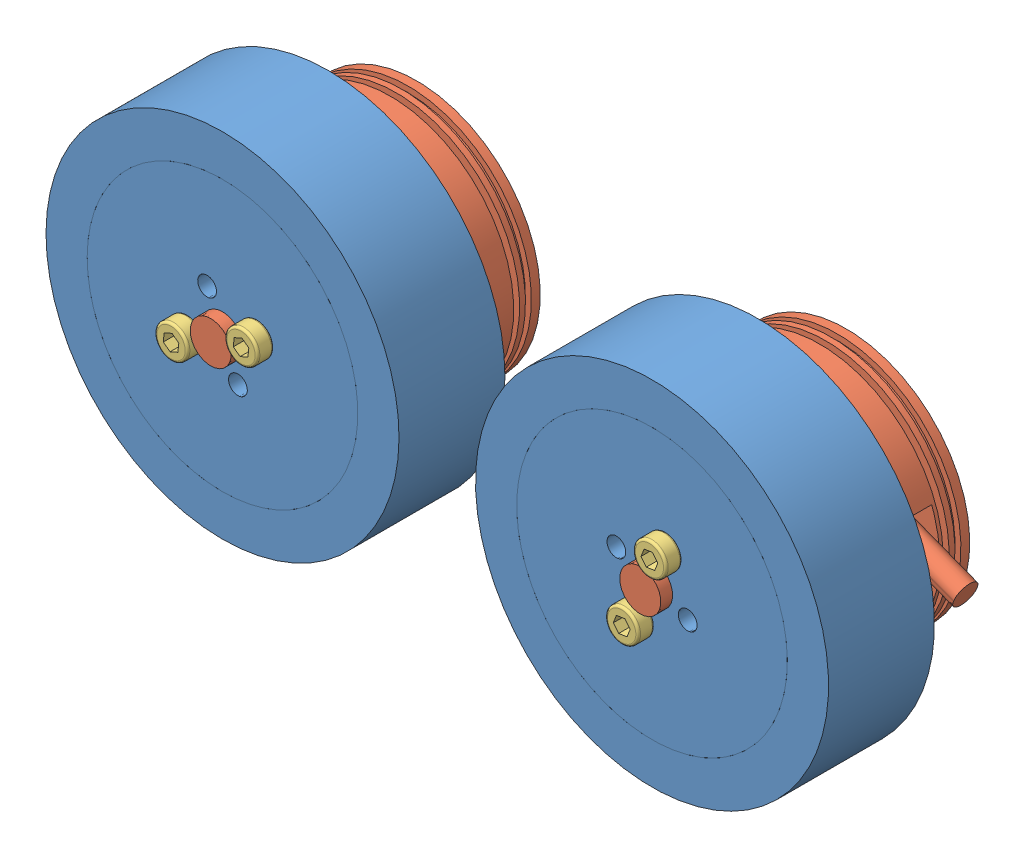
SolidWorks assembly 摩擦轮asm, configuration 默认. Lengths in mm.
Overall size (151.37 94.55 99.1).
11 component instances, 4 part files, 6 mates.
Components (placement in the parent):
- 大弹丸发射摩擦轮-1: 大弹丸发射摩擦轮 [默认] at (22.2893 6.1286 155.6267) x (0.362085 0.932145 0) z (0.932145 -0.362085 0) size (60 99.1 60)
  - 大弹丸发射摩擦轮-2: 大弹丸发射摩擦轮 [默认] x (-1 0 0) z (0 -1 0) size (60 60 18)
  - 3508去除减速箱-2: 3508去除减速箱 [默认] at (0 -41.7 0) x (0.999992 0 -0.003984) z (0.003984 0 0.999992) size (42 98.3 47)
  - 螺栓M3-6-1: 螺栓M3-6 [默认] at (-6.5 -6 0) size (5.6 8.8 5.6)
  - 螺栓M3-6-2: 螺栓M3-6 [默认] at (6.5 -6 0) size (5.6 8.8 5.6)
- 大弹丸发射摩擦轮-2: 大弹丸发射摩擦轮 [默认] at (-50.7107 6.1286 155.6267) x (0.915159 0.403094 0) z (0.403094 -0.915159 0) size (60 99.1 60)
  - 大弹丸发射摩擦轮-2: 大弹丸发射摩擦轮 [默认] x (-1 0 0) z (0 -1 0) size (60 60 18)
  - 3508去除减速箱-2: 3508去除减速箱 [默认] at (0 -41.7 0) x (0.999992 0 -0.003984) z (0.003984 0 0.999992) size (42 98.3 47)
  - 螺栓M3-6-1: 螺栓M3-6 [默认] at (-6.5 -6 0) size (5.6 8.8 5.6)
  - 螺栓M3-6-2: 螺栓M3-6 [默认] at (6.5 -6 0) size (5.6 8.8 5.6)
- 摩擦轮安装板1.1-1: 摩擦轮安装板1.1 [默认] at (-14.2107 6.1286 116.6267) size (123 86 6)
Mates (geometry in assembly coordinates):
- 同心1: concentric anti-aligned: circle of 摩擦轮安装板-1; circle of 大弹丸发射摩擦轮-1/3508去除减速箱-2
- 同心2: concentric aligned: cylinder of 摩擦轮安装板1.1-1 through (-50.7107 6.1286 122.6267) axis (0 0 -1) radius 13.4; circle of 大弹丸发射摩擦轮-2/3508去除减速箱-2
- 同心3: concentric anti-aligned: circle of 大弹丸发射摩擦轮-1/3508去除减速箱-2; circle of 摩擦轮安装板-1
- 重合3: coincident anti-aligned: plane of 摩擦轮安装板1.1-1 through (22.2893 6.1286 122.6267) normal (0 0 1); plane of 大弹丸发射摩擦轮-1/3508去除减速箱-2 through (47.5274 -26.0535 122.6267) normal (0 0 -1)
- 重合4: coincident anti-aligned: plane of 摩擦轮安装板1.1-1 through (22.2893 6.1286 122.6267) normal (0 0 1); plane of 大弹丸发射摩擦轮-2/3508去除减速箱-2 through (-55.6208 -34.4736 122.6267) normal (0 0 -1)
- 同心5: concentric aligned: cylinder of 摩擦轮安装板1.1-1 through (-50.7107 -11.3714 122.6267) axis (0 0 -1) radius 1.6; cylinder of 大弹丸发射摩擦轮-2/3508去除减速箱-2 through (-50.7107 -11.3714 130.6267) axis (0 0 -1) radius 1.25
